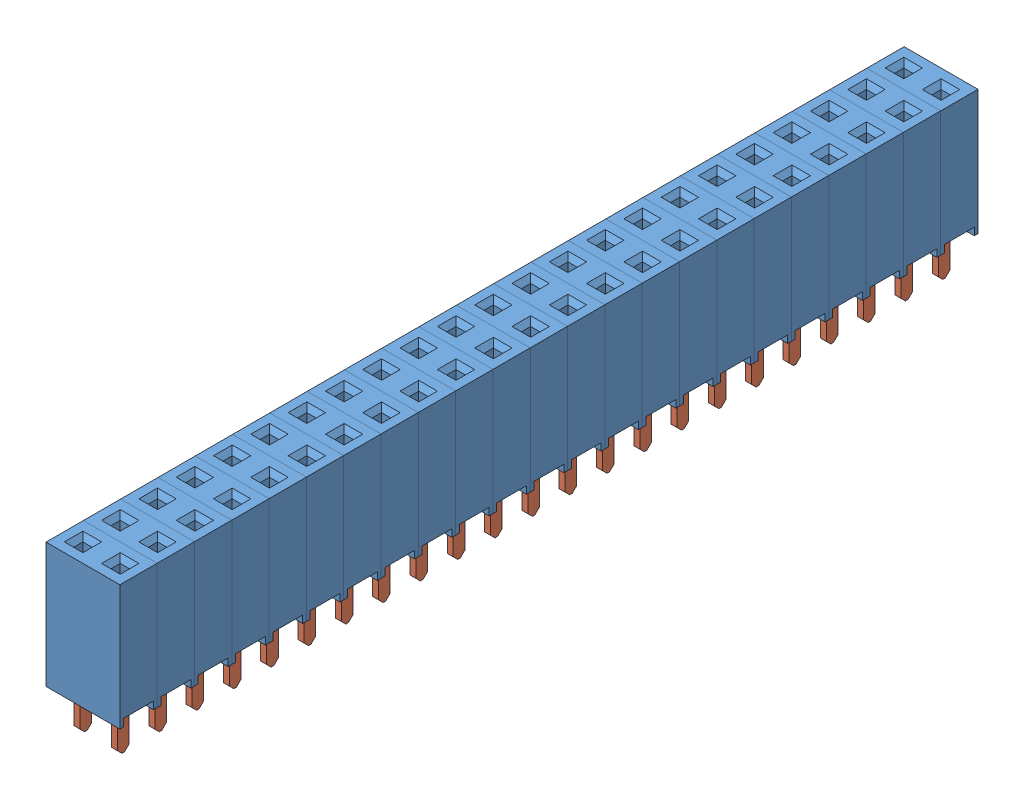
SolidWorks assembly SSHS-123-D-02-GT-LF, configuration Default. Lengths in mm.
Overall size (5.03 11.05 58.42).
69 component instances, 2 part files, 0 mates.
Components (placement in the parent):
- SSH-1-D-50-1: SSH-1-D-50 [Default] at origin size (5.03 8.51 2.54)
- C-025-02-T-1: C-025-02-T [Default] at (2.54 -0.3048 0) x (0 0 1) z (1 0 0) size (1.99 9.43 0.41)
- C-025-02-T-2: C-025-02-T [Default] at (0 -0.3048 0) x (0 0 -1) z (-1 0 0) size (1.99 9.43 0.41)
- C-025-02-T-3: C-025-02-T [Default] at (2.54 -0.3048 2.54) x (0 0 1) z (1 0 0) size (1.99 9.43 0.41)
- C-025-02-T-4: C-025-02-T [Default] at (2.54 -0.3048 5.08) x (0 0 1) z (1 0 0) size (1.99 9.43 0.41)
- C-025-02-T-5: C-025-02-T [Default] at (2.54 -0.3048 7.62) x (0 0 1) z (1 0 0) size (1.99 9.43 0.41)
- C-025-02-T-6: C-025-02-T [Default] at (2.54 -0.3048 10.16) x (0 0 1) z (1 0 0) size (1.99 9.43 0.41)
- C-025-02-T-7: C-025-02-T [Default] at (2.54 -0.3048 12.7) x (0 0 1) z (1 0 0) size (1.99 9.43 0.41)
- C-025-02-T-8: C-025-02-T [Default] at (2.54 -0.3048 15.24) x (0 0 1) z (1 0 0) size (1.99 9.43 0.41)
- C-025-02-T-9: C-025-02-T [Default] at (2.54 -0.3048 17.78) x (0 0 1) z (1 0 0) size (1.99 9.43 0.41)
- C-025-02-T-10: C-025-02-T [Default] at (2.54 -0.3048 20.32) x (0 0 1) z (1 0 0) size (1.99 9.43 0.41)
- C-025-02-T-11: C-025-02-T [Default] at (2.54 -0.3048 22.86) x (0 0 1) z (1 0 0) size (1.99 9.43 0.41)
- C-025-02-T-12: C-025-02-T [Default] at (2.54 -0.3048 25.4) x (0 0 1) z (1 0 0) size (1.99 9.43 0.41)
- C-025-02-T-13: C-025-02-T [Default] at (2.54 -0.3048 27.94) x (0 0 1) z (1 0 0) size (1.99 9.43 0.41)
- C-025-02-T-14: C-025-02-T [Default] at (2.54 -0.3048 30.48) x (0 0 1) z (1 0 0) size (1.99 9.43 0.41)
- C-025-02-T-15: C-025-02-T [Default] at (2.54 -0.3048 33.02) x (0 0 1) z (1 0 0) size (1.99 9.43 0.41)
- C-025-02-T-16: C-025-02-T [Default] at (2.54 -0.3048 35.56) x (0 0 1) z (1 0 0) size (1.99 9.43 0.41)
- C-025-02-T-17: C-025-02-T [Default] at (2.54 -0.3048 38.1) x (0 0 1) z (1 0 0) size (1.99 9.43 0.41)
- C-025-02-T-18: C-025-02-T [Default] at (2.54 -0.3048 40.64) x (0 0 1) z (1 0 0) size (1.99 9.43 0.41)
- C-025-02-T-19: C-025-02-T [Default] at (2.54 -0.3048 43.18) x (0 0 1) z (1 0 0) size (1.99 9.43 0.41)
- C-025-02-T-20: C-025-02-T [Default] at (2.54 -0.3048 45.72) x (0 0 1) z (1 0 0) size (1.99 9.43 0.41)
- C-025-02-T-21: C-025-02-T [Default] at (2.54 -0.3048 48.26) x (0 0 1) z (1 0 0) size (1.99 9.43 0.41)
- C-025-02-T-22: C-025-02-T [Default] at (2.54 -0.3048 50.8) x (0 0 1) z (1 0 0) size (1.99 9.43 0.41)
- C-025-02-T-23: C-025-02-T [Default] at (2.54 -0.3048 53.34) x (0 0 1) z (1 0 0) size (1.99 9.43 0.41)
- C-025-02-T-24: C-025-02-T [Default] at (2.54 -0.3048 55.88) x (0 0 1) z (1 0 0) size (1.99 9.43 0.41)
- C-025-02-T-25: C-025-02-T [Default] at (0 -0.3048 2.54) x (0 0 -1) z (-1 0 0) size (1.99 9.43 0.41)
- C-025-02-T-26: C-025-02-T [Default] at (0 -0.3048 5.08) x (0 0 -1) z (-1 0 0) size (1.99 9.43 0.41)
- C-025-02-T-27: C-025-02-T [Default] at (0 -0.3048 7.62) x (0 0 -1) z (-1 0 0) size (1.99 9.43 0.41)
- C-025-02-T-28: C-025-02-T [Default] at (0 -0.3048 10.16) x (0 0 -1) z (-1 0 0) size (1.99 9.43 0.41)
- C-025-02-T-29: C-025-02-T [Default] at (0 -0.3048 12.7) x (0 0 -1) z (-1 0 0) size (1.99 9.43 0.41)
- C-025-02-T-30: C-025-02-T [Default] at (0 -0.3048 15.24) x (0 0 -1) z (-1 0 0) size (1.99 9.43 0.41)
- C-025-02-T-31: C-025-02-T [Default] at (0 -0.3048 17.78) x (0 0 -1) z (-1 0 0) size (1.99 9.43 0.41)
- C-025-02-T-32: C-025-02-T [Default] at (0 -0.3048 20.32) x (0 0 -1) z (-1 0 0) size (1.99 9.43 0.41)
- C-025-02-T-33: C-025-02-T [Default] at (0 -0.3048 22.86) x (0 0 -1) z (-1 0 0) size (1.99 9.43 0.41)
- C-025-02-T-34: C-025-02-T [Default] at (0 -0.3048 25.4) x (0 0 -1) z (-1 0 0) size (1.99 9.43 0.41)
- C-025-02-T-35: C-025-02-T [Default] at (0 -0.3048 27.94) x (0 0 -1) z (-1 0 0) size (1.99 9.43 0.41)
- C-025-02-T-36: C-025-02-T [Default] at (0 -0.3048 30.48) x (0 0 -1) z (-1 0 0) size (1.99 9.43 0.41)
- C-025-02-T-37: C-025-02-T [Default] at (0 -0.3048 33.02) x (0 0 -1) z (-1 0 0) size (1.99 9.43 0.41)
- C-025-02-T-38: C-025-02-T [Default] at (0 -0.3048 35.56) x (0 0 -1) z (-1 0 0) size (1.99 9.43 0.41)
- C-025-02-T-39: C-025-02-T [Default] at (0 -0.3048 38.1) x (0 0 -1) z (-1 0 0) size (1.99 9.43 0.41)
- C-025-02-T-40: C-025-02-T [Default] at (0 -0.3048 40.64) x (0 0 -1) z (-1 0 0) size (1.99 9.43 0.41)
- C-025-02-T-41: C-025-02-T [Default] at (0 -0.3048 43.18) x (0 0 -1) z (-1 0 0) size (1.99 9.43 0.41)
- C-025-02-T-42: C-025-02-T [Default] at (0 -0.3048 45.72) x (0 0 -1) z (-1 0 0) size (1.99 9.43 0.41)
- C-025-02-T-43: C-025-02-T [Default] at (0 -0.3048 48.26) x (0 0 -1) z (-1 0 0) size (1.99 9.43 0.41)
- C-025-02-T-44: C-025-02-T [Default] at (0 -0.3048 50.8) x (0 0 -1) z (-1 0 0) size (1.99 9.43 0.41)
- C-025-02-T-45: C-025-02-T [Default] at (0 -0.3048 53.34) x (0 0 -1) z (-1 0 0) size (1.99 9.43 0.41)
- C-025-02-T-46: C-025-02-T [Default] at (0 -0.3048 55.88) x (0 0 -1) z (-1 0 0) size (1.99 9.43 0.41)
- SSH-1-D-50-2: SSH-1-D-50 [Default] at (0 0 2.54) size (5.03 8.51 2.54)
- SSH-1-D-50-3: SSH-1-D-50 [Default] at (0 0 5.08) size (5.03 8.51 2.54)
- SSH-1-D-50-4: SSH-1-D-50 [Default] at (0 0 7.62) size (5.03 8.51 2.54)
- SSH-1-D-50-5: SSH-1-D-50 [Default] at (0 0 10.16) size (5.03 8.51 2.54)
- SSH-1-D-50-6: SSH-1-D-50 [Default] at (0 0 12.7) size (5.03 8.51 2.54)
- SSH-1-D-50-7: SSH-1-D-50 [Default] at (0 0 15.24) size (5.03 8.51 2.54)
- SSH-1-D-50-8: SSH-1-D-50 [Default] at (0 0 17.78) size (5.03 8.51 2.54)
- SSH-1-D-50-9: SSH-1-D-50 [Default] at (0 0 20.32) size (5.03 8.51 2.54)
- SSH-1-D-50-10: SSH-1-D-50 [Default] at (0 0 22.86) size (5.03 8.51 2.54)
- SSH-1-D-50-11: SSH-1-D-50 [Default] at (0 0 25.4) size (5.03 8.51 2.54)
- SSH-1-D-50-12: SSH-1-D-50 [Default] at (0 0 27.94) size (5.03 8.51 2.54)
- SSH-1-D-50-13: SSH-1-D-50 [Default] at (0 0 30.48) size (5.03 8.51 2.54)
- SSH-1-D-50-14: SSH-1-D-50 [Default] at (0 0 33.02) size (5.03 8.51 2.54)
- SSH-1-D-50-15: SSH-1-D-50 [Default] at (0 0 35.56) size (5.03 8.51 2.54)
- SSH-1-D-50-16: SSH-1-D-50 [Default] at (0 0 38.1) size (5.03 8.51 2.54)
- SSH-1-D-50-17: SSH-1-D-50 [Default] at (0 0 40.64) size (5.03 8.51 2.54)
- SSH-1-D-50-18: SSH-1-D-50 [Default] at (0 0 43.18) size (5.03 8.51 2.54)
- SSH-1-D-50-19: SSH-1-D-50 [Default] at (0 0 45.72) size (5.03 8.51 2.54)
- SSH-1-D-50-20: SSH-1-D-50 [Default] at (0 0 48.26) size (5.03 8.51 2.54)
- SSH-1-D-50-21: SSH-1-D-50 [Default] at (0 0 50.8) size (5.03 8.51 2.54)
- SSH-1-D-50-22: SSH-1-D-50 [Default] at (0 0 53.34) size (5.03 8.51 2.54)
- SSH-1-D-50-23: SSH-1-D-50 [Default] at (0 0 55.88) size (5.03 8.51 2.54)
